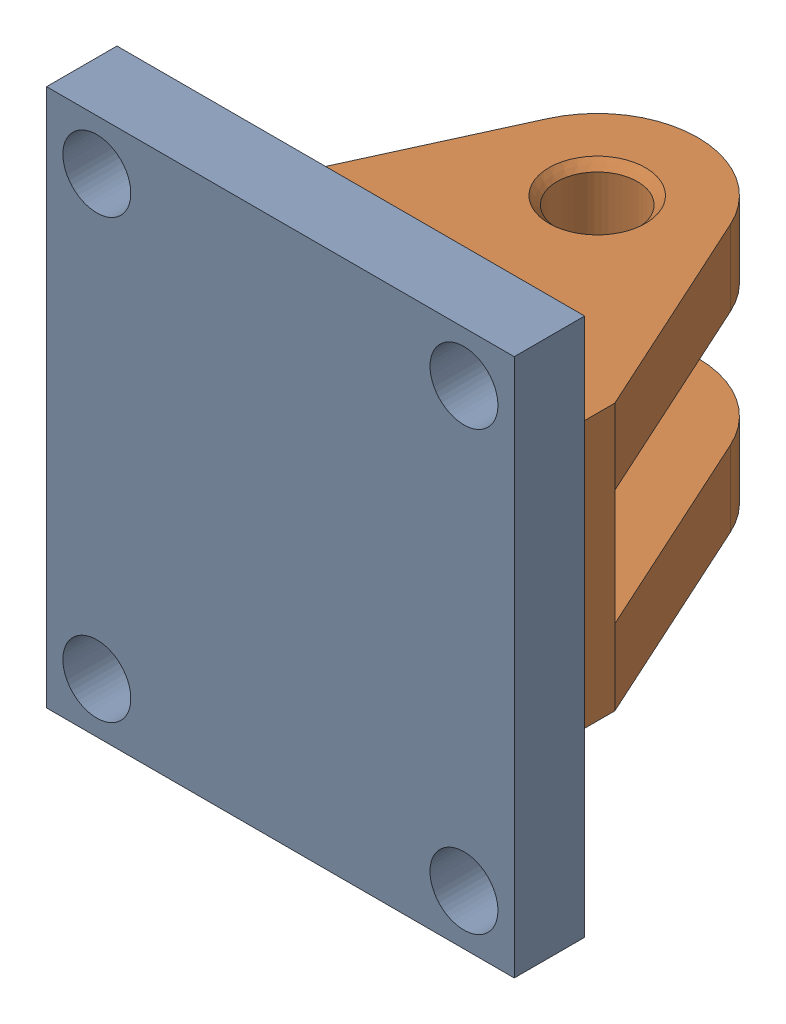
SolidWorks assembly Sestava konzoly, configuration Výchozí. Lengths in mm.
Overall size (93 107 83).
2 component instances, 2 part files, 3 mates.
Components (placement in the parent):
- Deska-1: Deska [Výchozí] at (-134.6121 27.1092 -7) size (93 107 14)
- Vidlice-1: Vidlice [Výchozí] at (-134.6121 38.6092 -7) x (1 0 0) z (0 1 0) size (75 69 53)
Mates (geometry in assembly coordinates):
- Sjednocená1: coincident anti-aligned: plane of Deska-1 through (-134.6121 27.1092 -6.9999) normal (0 0 -1); plane of Vidlice-1 through (-172.1121 53.6092 -7) normal (0 0 1)
- Sjednocená2: coincident anti-aligned: line of Deska-1 through (-172.1121 0.6092 -7) axis (0 1 0); line of Vidlice-1 through (-172.1121 53.6092 -7) axis (0 -1 0)
- Sjednocená3: coincident anti-aligned: line of Deska-1 through (-97.1121 0.6092 -7) axis (-1 0 0); line of Vidlice-1 through (-172.1121 0.6092 -7) axis (1 0 0)
